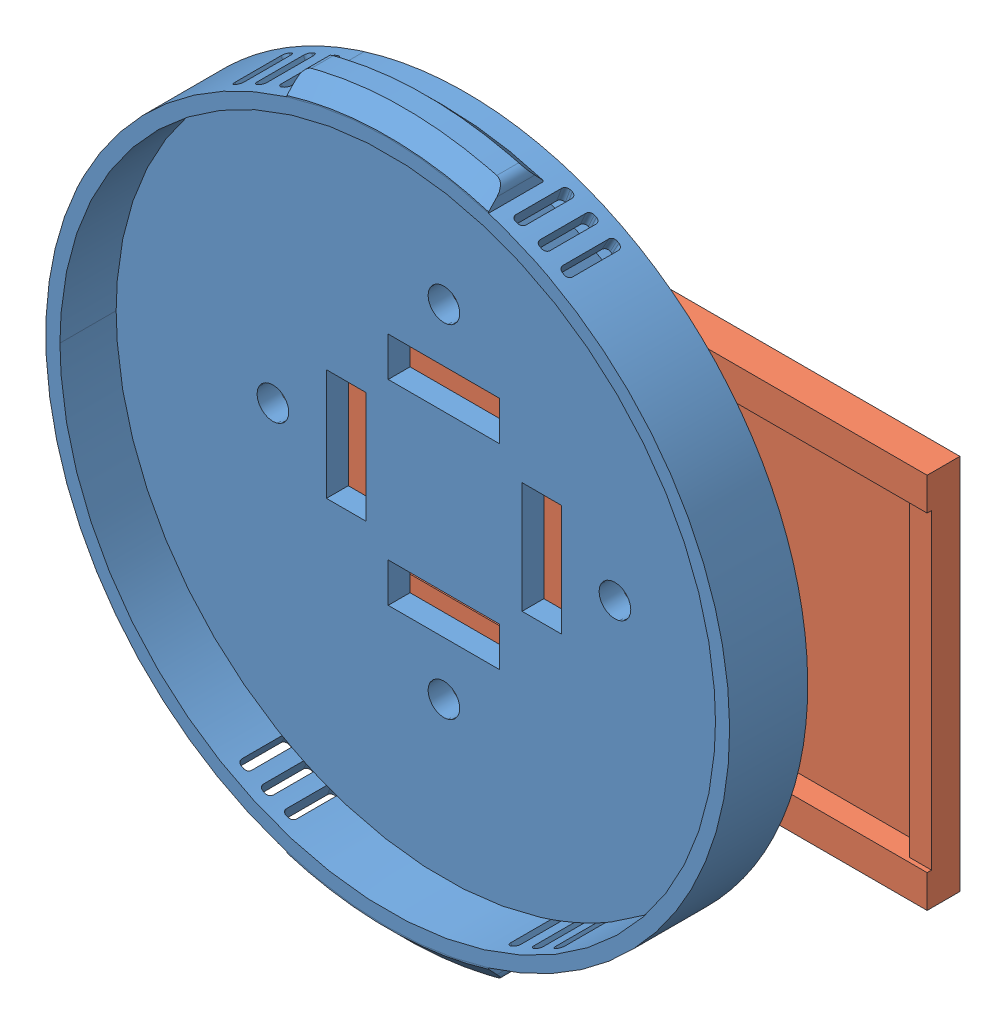
SolidWorks assembly MoonWithServo, configuration Default. Lengths in mm.
Overall size (68.71 68.1 14.96).
3 component instances, 3 part files, 12 mates.
Components (placement in the parent):
- LED Lamp Kitv2-1: LED Lamp Kitv2 [Default] at (8.6735 41.6124 56.98) size (62.61 68.1 7.15)
- RegMoonThicker_conc-1: RegMoonThicker_conc [Default] at (-118.8265 -85.8876 64.8758) size (173.65 174 175.54) (hidden)
- jammer-1: jammer [Default] at (46.0826 41.6124 57.0558) x (0 1 0) z (1 0 0) size (34.5 3 59.15)
Mates (geometry in assembly coordinates):
- Coincident2: coincident aligned: plane of LED Lamp Kitv2-1 through (8.6735 41.6124 56.98) normal (0 1 0); plane of RegMoonThicker_conc-1 through (-118.8265 41.6124 64.8758) normal (0 1 0)
- Coincident3: coincident aligned: plane of LED Lamp Kitv2-1 through (8.6735 41.6124 56.98) normal (1 0 0); plane of RegMoonThicker_conc-1 through (8.6735 -85.8876 64.8758) normal (1 0 0)
- Concentric1: concentric anti-aligned: circle of LED Lamp Kit-001 Design Guide.stp-1; cylinder of Ass servo-1 through (8.6735 41.6124 64.8758) axis (0 0 1) radius 10
- Concentric3: concentric anti-aligned: cylinder of LED Lamp Kit-001 Design Guide.stp-1 through (15.6735 41.6124 72.02) axis (0 0 -1) radius 1.25; cylinder of Ass servo-1 through (15.6735 41.6124 64.8758) axis (0 0 1) radius 1.5
- Coincident5: coincident anti-aligned: plane of LED Lamp Kit-001 Design Guide.stp-1 through (8.6735 41.6124 66.8758) normal (0 0 -1); plane of Ass servo-1 through (8.6735 41.6124 66.8758) normal (0 0 1)
- Concentric4: concentric anti-aligned: cylinder of LED Lamp Kit-001 Design Guide.stp-1 through (15.6735 41.6124 72.02) axis (0 0 -1) radius 1.25; cylinder of Ass servo-1 through (15.6735 41.6124 64.8758) axis (0 0 1) radius 1.5
- Concentric5: concentric anti-aligned: cylinder of LED Lamp Kit-001 Design Guide.stp-1 through (8.6735 41.6124 66.8758) axis (0 0 -1) radius 10.25; cylinder of MG996R Servo Motor-1/Servo Horns-6 through (8.6735 41.6124 64.5758) axis (0 0 1) radius 10
- Concentric6: concentric anti-aligned: cylinder of LED Lamp Kit-001 Design Guide.stp-1 through (8.6735 48.6124 72.02) axis (0 0 -1) radius 1.25; cylinder of MG996R Servo Motor-1/Servo Horns-6 through (8.6735 48.6124 64.5758) axis (0 0 1) radius 0.75
- Coincident6: coincident anti-aligned: plane of LED Lamp Kit-001 Design Guide.stp-1 through (8.6735 41.6124 66.8758) normal (0 0 -1); plane of MG996R Servo Motor-1/Servo Horns-6 through (8.6735 41.6124 66.8758) normal (0 0 1)
- Coincident7: coincident: plane of LED Lamp Kit-001 Design Guide.stp-1 through (46.0826 41.6124 64.8758) normal (1 0 0); plane of jammer-1 through (46.0826 41.6124 59.6558) normal (1 0 0)
- Coincident10: coincident: plane of LED Lamp Kit-001 Design Guide.stp-1 through (-47.6976 24.3624 60.0558) normal (0 1 0); plane of jammer-1 through (46.0826 24.3624 59.6558) normal (0 -1 0)
- Coincident11: coincident: plane of LED Lamp Kit-001 Design Guide.stp-1 through (-47.6976 24.3624 57.0558) normal (0 0 1); plane of jammer-1 through (46.0826 41.6124 57.0558) normal (0 0 -1)
